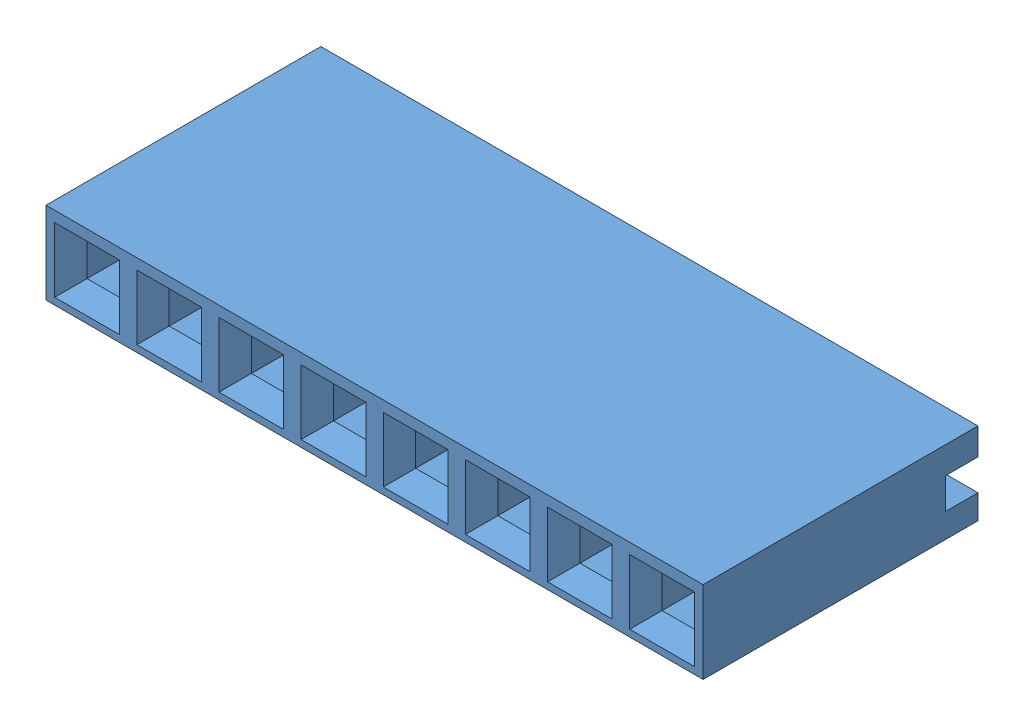
SolidWorks assembly 960240-6202-AR 1x8 long, configuration Default. Lengths in mm.
Overall size (20.32 2.54 18.99).
9 component instances, 2 part files, 4 mates.
Components (placement in the parent):
- 960240-6202-AR Body8-1: 960240-6202-AR Body8 [Default] at (10.16 -1.27 8.5) size (20.32 2.54 8.5)
- 960240-6202-AR Pin Long-1: 960240-6202-AR Pin Long [Default] at (8.89 0.04 -0.7572) x (1 0 0) z (0 -1 0) size (2 16.99 0.4)
- 960240-6202-AR Pin Long-3: 960240-6202-AR Pin Long [Default] at (6.35 0.04 -0.7572) x (1 0 0) z (0 -1 0) size (2 16.99 0.4)
- 960240-6202-AR Pin Long-5: 960240-6202-AR Pin Long [Default] at (3.81 0.04 -0.7572) x (1 0 0) z (0 -1 0) size (2 16.99 0.4)
- 960240-6202-AR Pin Long-7: 960240-6202-AR Pin Long [Default] at (1.27 0.04 -0.7572) x (1 0 0) z (0 -1 0) size (2 16.99 0.4)
- 960240-6202-AR Pin Long-9: 960240-6202-AR Pin Long [Default] at (-1.27 0.04 -0.7572) x (1 0 0) z (0 -1 0) size (2 16.99 0.4)
- 960240-6202-AR Pin Long-11: 960240-6202-AR Pin Long [Default] at (-3.81 0.04 -0.7572) x (1 0 0) z (0 -1 0) size (2 16.99 0.4)
- 960240-6202-AR Pin Long-13: 960240-6202-AR Pin Long [Default] at (-6.35 0.04 -0.7572) x (1 0 0) z (0 -1 0) size (2 16.99 0.4)
- 960240-6202-AR Pin Long-15: 960240-6202-AR Pin Long [Default] at (-8.89 0.04 -0.7572) x (1 0 0) z (0 -1 0) size (2 16.99 0.4)
Mates (geometry in assembly coordinates):
- Coincident1: coincident anti-aligned: plane of 960240-6202-AR Pin Long-1 through (8.9056 -0.16 -10.2904) normal (0 -1 0); plane of 960240-6202-AR Body8-1 through (7.89 -0.16 6.5) normal (0 1 0)
- Tangent1: tangent anti-aligned: plane of 960240-6202-AR Body8-1 through (10.16 -1.27 6.5) normal (0 0 -1); cylinder of 960240-6202-AR Pin Long-1 through (9.69 0.24 6.3) axis (0 -1 0) radius 0.2
- Coincident2: coincident anti-aligned: plane of 960240-6202-AR Body8-1 through (9.89 -0.16 6.5) normal (-1 0 0); plane of 960240-6202-AR Pin Long-1 through (9.89 0.24 0.9096) normal (1 0 0)
- Coincident5: coordinate: point of 960240-6202-AR Body8-1; point of assembly
